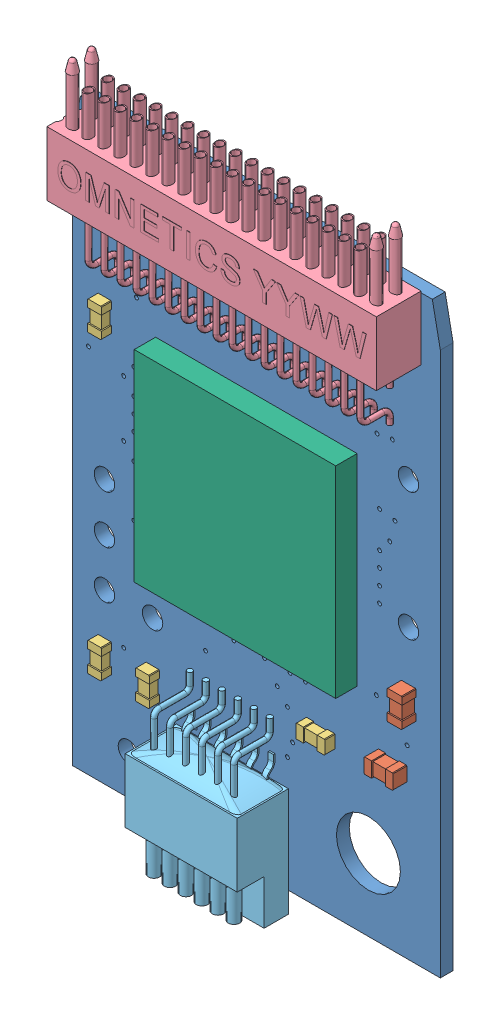
SolidWorks assembly RHD2216_headstage, configuration Default. Lengths in mm.
Overall size (14.61 26.43 2.55).
10 component instances, 6 part files, 20 mates.
Components (placement in the parent):
- RHD2216_RHD2132_headstage_PCB-1: RHD2216_RHD2132_headstage_PCB [Default] at origin size (14.61 23.18 0.51)
- 0402c_2320560-1: 0402c_2320560 [Default] at (13.335 8.89 0.508) x (0 -1 0) z (0 0 1) size (1.15 0.6 0.55)
- 0402c_2320560-2: 0402c_2320560 [Default] at (12.7 6.35 0.508) size (1.15 0.6 0.55)
- 0402r_1430758-1: 0402r_1430758 [Default] at (1.27 16.18 0.508) x (0 -1 0) z (0 0 1) size (1.15 0.55 0.4)
- 0402r_1430758-2: 0402r_1430758 [Default] at (3.175 4.445 0.508) x (0 1 0) z (0 0 1) size (1.15 0.55 0.4)
- 0402r_1430758-3: 0402r_1430758 [Default] at (1.27 4.445 0.508) x (0 1 0) z (0 0 1) size (1.15 0.55 0.4)
- 0402r_1430758-4: 0402r_1430758 [Default] at (9.8425 6.0325 0.508) size (1.15 0.55 0.4)
- A79025-001-1: A79025-001 [Default] at (6.0325 21.971 2.286) size (13.15 7.44 2.12)
- A79623-001-1: A79623-001 [Default] at (6.35 3.4925 0.508) x (1 0 0) z (0 -1 0) size (4.45 2.05 6.53)
- QFN_8x8mm-1: QFN_8x8mm [Default] at (3.3025 8.3825 0.508) x (1 0 0) z (0 -1 0) size (8 0.85 8)
Mates (geometry in assembly coordinates):
- Coincident1: coincident anti-aligned: plane of RHD2216_RHD2132_headstage-1 through (0 0 0.508) normal (0 0 1); plane of A79025-001-1 through (13.843 20.701 0.508) normal (0 0 -1)
- Parallel1: parallel aligned: plane of RHD2216_RHD2132_headstage-1 through (0.3175 23.1775 0.508) normal (0 1 0); plane of A79025-001-1 through (13.843 23.241 2.286) normal (0 1 0)
- Distance1: distance = 0.0635 mm: line of A79025-001-1 through (0.762 23.241 0.508) axis (1 0 0); line of RHD2216_RHD2132_headstage-1 through (14.2875 23.1775 0.508) axis (-1 0 0)
- Distance3: distance = 0.762 mm: line of A79025-001-1 through (0.762 20.7271 0.508) axis (0 1 0); line of RHD2216_RHD2132_headstage-1 through (0 21.59 0.508) axis (0 -1 0)
- Coincident5: coincident anti-aligned: plane of RHD2216_RHD2132_headstage-1 through (0 0 0.508) normal (0 0 1); plane of QFN_8x8mm-1 through (3.3025 8.3825 0.508) normal (0 0 -1)
- Parallel2: parallel aligned: plane of RHD2216_RHD2132_headstage-1 through (14.605 21.59 0.508) normal (1 0 0); plane of QFN_8x8mm-1 through (11.3025 8.3825 1.358) normal (1 0 0)
- Coincident6: coincident anti-aligned: plane of RHD2216_RHD2132_headstage-1 through (0 0 0.508) normal (0 0 1); plane of A79623-001-1 through (6.35 3.4925 0.508) normal (0 0 -1)
- Parallel3: parallel aligned: plane of RHD2216_RHD2132_headstage-1 through (14.605 0 0.508) normal (0 -1 0); plane of A79623-001-1 through (8.5725 -0.8255 0.508) normal (0 -1 0)
- Coincident7: coincident anti-aligned: plane of RHD2216_RHD2132_headstage-1 through (0 0 0.508) normal (0 0 1); plane of 0402r_1430758-1 through (2.095 16.18 0.508) normal (0 0 -1)
- Parallel4: parallel aligned: plane of RHD2216_RHD2132_headstage-1 through (14.605 0 0.508) normal (0 -1 0); plane of 0402r_1430758-1 through (1.02 15.605 0.908) normal (0 -1 0)
- Coincident8: coincident anti-aligned: plane of RHD2216_RHD2132_headstage-1 through (0 0 0.508) normal (0 0 1); plane of 0402r_1430758-3 through (0.445 4.445 0.508) normal (0 0 -1)
- Parallel5: parallel aligned: plane of RHD2216_RHD2132_headstage-1 through (14.605 0 0.508) normal (0 -1 0); plane of 0402r_1430758-3 through (1.02 3.87 0.908) normal (0 -1 0)
- Coincident9: coincident anti-aligned: plane of RHD2216_RHD2132_headstage-1 through (0 0 0.508) normal (0 0 1); plane of 0402r_1430758-2 through (2.35 4.445 0.508) normal (0 0 -1)
- Parallel6: parallel aligned: plane of RHD2216_RHD2132_headstage-1 through (14.605 0 0.508) normal (0 -1 0); plane of 0402r_1430758-2 through (2.925 3.87 0.908) normal (0 -1 0)
- Coincident10: coincident anti-aligned: plane of RHD2216_RHD2132_headstage-1 through (0 0 0.508) normal (0 0 1); plane of 0402r_1430758-4 through (9.8425 6.8575 0.508) normal (0 0 -1)
- Parallel7: parallel aligned: plane of RHD2216_RHD2132_headstage-1 through (14.605 21.59 0.508) normal (1 0 0); plane of 0402r_1430758-4 through (10.4175 5.7825 0.908) normal (1 0 0)
- Coincident11: coincident anti-aligned: plane of RHD2216_RHD2132_headstage-1 through (0 0 0.508) normal (0 0 1); plane of 0402c_2320560-2 through (12.7 7.2 0.508) normal (0 0 -1)
- Parallel8: parallel aligned: plane of RHD2216_RHD2132_headstage-1 through (14.605 21.59 0.508) normal (1 0 0); plane of 0402c_2320560-2 through (13.275 6.075 1.058) normal (1 0 0)
- Coincident12: coincident anti-aligned: plane of RHD2216_RHD2132_headstage-1 through (0 0 0.508) normal (0 0 1); plane of 0402c_2320560-1 through (14.185 8.89 0.508) normal (0 0 -1)
- Parallel9: parallel aligned: plane of RHD2216_RHD2132_headstage-1 through (14.605 0 0.508) normal (0 -1 0); plane of 0402c_2320560-1 through (13.06 8.315 1.058) normal (0 -1 0)
